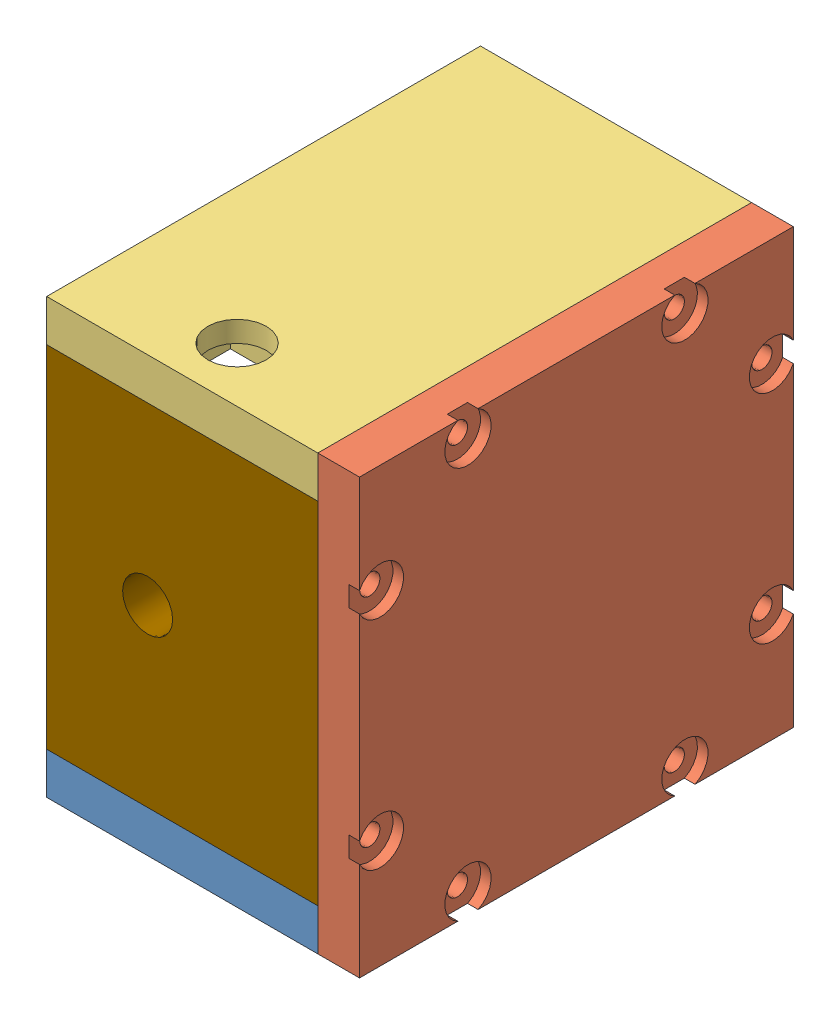
SolidWorks assembly Na_EOM_assembly_v1, configuration Default. Lengths in mm.
Overall size (37.5 52 52).
11 component instances, 10 part files, 22 mates.
Components (placement in the parent):
- Na_EOM_bottom_plate-1: Na_EOM_bottom_plate [Default] at (-34.7103 -17.6253 62.9537) size (32.5 5 52)
- Na_EOM_side_plate-1: Na_EOM_side_plate [Default] at (-2.2103 -17.6253 62.9537) size (5 52 52)
- Na_EOM_top_plate-1: Na_EOM_top_plate [Default] at (-34.7103 29.3747 62.9537) size (32.5 5 52)
- Na_EOM_side_plate-2: Na_EOM_side_plate [Default] at (-34.7103 -17.6253 10.9537) x (-1 0 0) z (0 0 -1) size (5 52 52) (hidden)
- Na_EOM_crystal-1: Na_EOM_crystal [Default] at (-24.4603 6.8747 28.9737) size (3 3 25.41)
- Part3^Na_EOM_assembly_v1-1: Part3^Na_EOM_assembly_v1 [Default] at origin (virtual)
- Na_EOM_plexiglass_bottom_v1-3: Na_EOM_plexiglass_bottom_v1 [Default] at (-27.7103 -12.6253 28.9737) x (0 0 1) z (-1 0 0) size (25.41 15 18.5)
- Na_EOM_cavity_lower_v1-2: Na_EOM_cavity_lower_v1 [Default] at (-12.4603 2.3747 54.3837) x (0 0 -1) z (1 0 0) size (25.41 6 12)
- Na_EOM_cavity_upper_v1-2: Na_EOM_cavity_upper_v1 [Default] at (-12.4603 14.3747 28.9737) x (0 0 1) z (1 0 0) size (25.41 6 12)
- Na_EOM_front_plate_v1-1: Na_EOM_front_plate_v1 [Default] at (-34.7103 -12.6253 10.9537) size (32.5 42 5)
- Na_EOM_back_plate_v1-1: Na_EOM_back_plate_v1 [Default] at (-34.7103 -12.6253 57.9537) size (32.5 42 5)
Mates (geometry in assembly coordinates):
- Coincident3: coincident aligned: plane of Na_EOM_bottom_plate-1 through (-34.7103 -12.6253 62.9537) normal (0 0 1); plane of Na_EOM_side_plate-1 through (2.7897 -17.6253 62.9537) normal (0 0 1)
- Coincident5: coincident anti-aligned: plane of Na_EOM_bottom_plate-1 through (-2.2103 -12.6253 62.9537) normal (1 0 0); plane of Na_EOM_side_plate-1 through (-2.2103 -17.6253 62.9537) normal (-1 0 0)
- Coincident6: coincident aligned: plane of Na_EOM_bottom_plate-1 through (-34.7103 -17.6253 62.9537) normal (0 -1 0); plane of Na_EOM_side_plate-1 through (2.7897 -17.6253 62.9537) normal (0 -1 0)
- Coincident7: coincident aligned: plane of Na_EOM_side_plate-1 through (2.7897 34.3747 62.9537) normal (0 1 0); plane of Na_EOM_top_plate-1 through (-34.7103 34.3747 62.9537) normal (0 1 0)
- Coincident9: coincident aligned: plane of Na_EOM_side_plate-1 through (2.7897 -17.6253 62.9537) normal (0 0 1); plane of Na_EOM_top_plate-1 through (-34.7103 34.3747 62.9537) normal (0 0 1)
- Coincident10: coincident anti-aligned: plane of Na_EOM_side_plate-1 through (-2.2103 -17.6253 62.9537) normal (-1 0 0); plane of Na_EOM_top_plate-1 through (-2.2103 34.3747 62.9537) normal (1 0 0)
- Coincident59: coincident anti-aligned: line of Na_EOM_top_plate-1 through (-34.7103 34.3747 10.9537) axis (0 0 1); line of Na_EOM_side_plate-2 through (-34.7103 34.3747 62.9537) axis (0 0 -1)
- Parallel1: parallel aligned: line of Na_EOM_top_plate-1 through (-34.7103 34.3747 10.9537) axis (0 -1 0); line of Na_EOM_side_plate-2 through (-39.7103 34.3747 10.9537) axis (0 -1 0)
- Concentric1: concentric anti-aligned: circle of Na_EOM_bottom_plate-1; circle of Na_EOM_plexiglass_bottom_v1-3
- Parallel3: parallel aligned: line of Na_EOM_bottom_plate-1 through (-34.7103 -12.6253 10.9537) axis (0 0 1); line of Na_EOM_plexiglass_bottom_v1-3 through (-27.7103 -12.6253 28.9737) axis (0 0 1)
- Coincident63: coincident anti-aligned: plane of Na_EOM_bottom_plate-1 through (-34.7103 -12.6253 62.9537) normal (0 1 0); plane of Na_EOM_plexiglass_bottom_v1-3 through (-27.7103 -12.6253 28.9737) normal (0 -1 0)
- Concentric2: concentric aligned: circle of Na_EOM_plexiglass_bottom_v1-3; circle of Na_EOM_cavity_lower_v1-2
- Concentric3: concentric aligned: circle of Na_EOM_plexiglass_bottom_v1-3; circle of Na_EOM_cavity_lower_v1-2
- Coincident65: coincident anti-aligned: plane of Na_EOM_plexiglass_bottom_v1-3 through (-27.7103 2.3747 28.9737) normal (0 1 0); plane of Na_EOM_cavity_lower_v1-2 through (-12.4603 2.3747 54.3837) normal (0 -1 0)
- Coincident66: coincident aligned: line of Na_EOM_cavity_lower_v1-2 through (-12.4603 8.3747 28.9737) axis (-1 0 0); line of Na_EOM_cavity_upper_v1-2 through (-12.4603 8.3747 28.9737) axis (-1 0 0)
- Coincident67: coincident aligned: line of Na_EOM_cavity_lower_v1-2 through (-16.0403 8.3747 28.9737) axis (0 0 1); line of Na_EOM_cavity_upper_v1-2 through (-16.0403 8.3747 28.9737) axis (0 0 1)
- Coincident68: coincident anti-aligned: line of Na_EOM_crystal-1 through (-21.4603 9.8747 28.9737) axis (-1 0 0); line of Na_EOM_cavity_upper_v1-2 through (-24.4603 9.8747 28.9737) axis (1 0 0)
- Coincident69: coincident anti-aligned: line of Na_EOM_crystal-1 through (-24.4603 9.8747 28.9737) axis (0 -1 0); line of Na_EOM_cavity_upper_v1-2 through (-24.4603 9.8747 28.9737) axis (0 1 0)
- Coincident70: coincident aligned: line of Na_EOM_top_plate-1 through (-2.2103 29.3747 10.9537) axis (-1 0 0); line of Na_EOM_front_plate_v1-1 through (-2.2103 29.3747 10.9537) axis (-1 0 0)
- Coincident71: coincident aligned: line of Na_EOM_side_plate-1 through (-2.2103 -17.6253 10.9537) axis (0 1 0); line of Na_EOM_front_plate_v1-1 through (-2.2103 -12.6253 10.9537) axis (0 1 0)
- Coincident72: coincident anti-aligned: line of Na_EOM_side_plate-1 through (-2.2103 34.3747 62.9537) axis (0 -1 0); line of Na_EOM_back_plate_v1-1 through (-2.2103 -12.6253 62.9537) axis (0 1 0)
- Coincident73: coincident anti-aligned: line of Na_EOM_top_plate-1 through (-34.7103 29.3747 62.9537) axis (1 0 0); line of Na_EOM_back_plate_v1-1 through (-2.2103 29.3747 62.9537) axis (-1 0 0)
